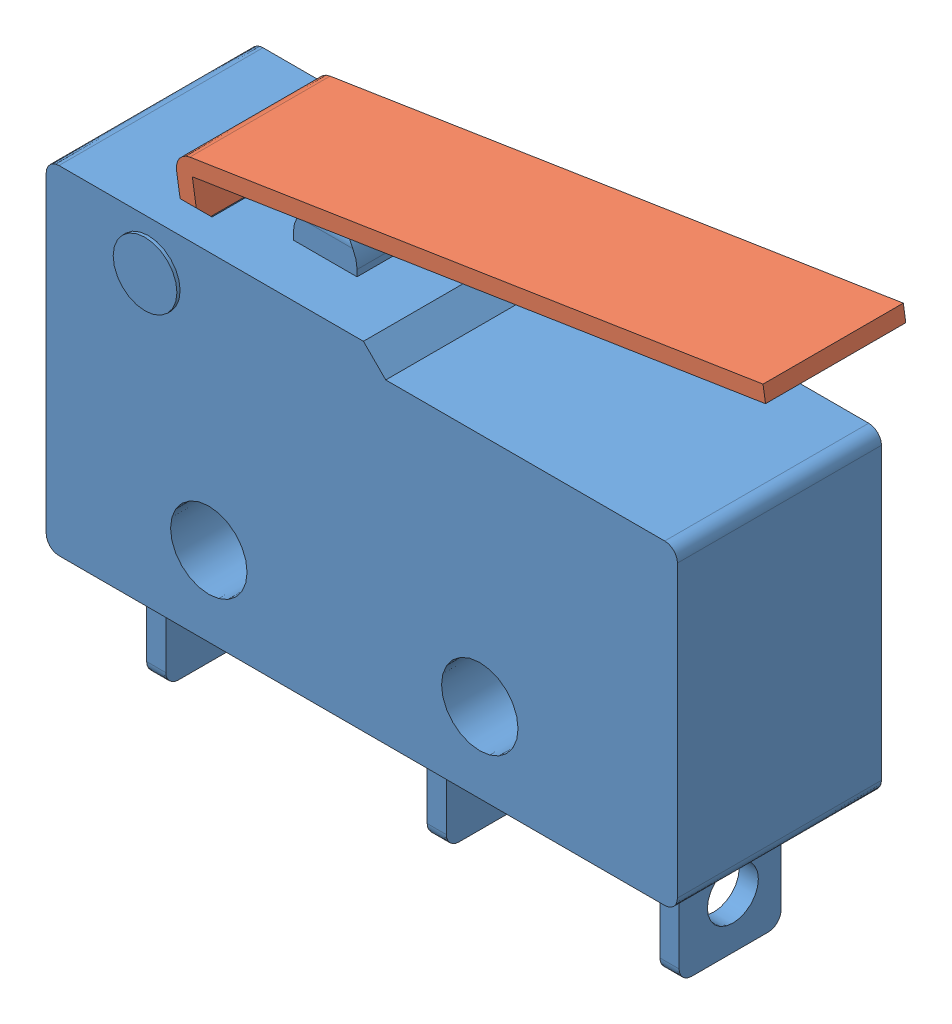
SolidWorks assembly MicroswitchSM-05S-02A0-Z, configuration Défaut. Lengths in mm.
Overall size (21.75 18.2 6.6).
2 component instances, 2 part files, 4 mates.
Components (placement in the parent):
- MicroswitchBase-1: MicroswitchBase [Défaut] at (-12.0234 -6.6808 19.8) size (19.8 15.3 6.6)
- MicroswitchLever-1: MicroswitchLever [Défaut] at (-8.7487 3.4432 20.8) x (0.987895 0.155121 0) z (0 0 1) size (18.7 1.7 4.4)
Mates (geometry in assembly coordinates):
- Tangent1: tangent anti-aligned: cylinder of MicroswitchBase-1 through (-8.8234 2.4192 26.3) axis (0 0 -1) radius 1; plane of MicroswitchLever-1 through (-8.2547 3.5207 25.2) normal (0.155121 -0.987895 0)
- Coïncidente1: coincident anti-aligned: plane of MicroswitchBase-1 through (-12.0234 2.3192 25.2) normal (0 0 -1); plane of MicroswitchLever-1 through (-8.7487 3.4432 25.2) normal (0 0 1)
- Tangent2: tangent: cylinder of MicroswitchBase-1 through (-4.9234 4.1192 19.8) axis (0 0 1) radius 1; plane of MicroswitchLever-1
- Coïncidente5: coincident: line of MicroswitchBase-1 through (-8.8234 3.9192 20.8) axis (0 0 1); plane of MicroswitchLever-1 through (-8.7487 3.4432 25.2) normal (-0.987895 -0.155121 0)
